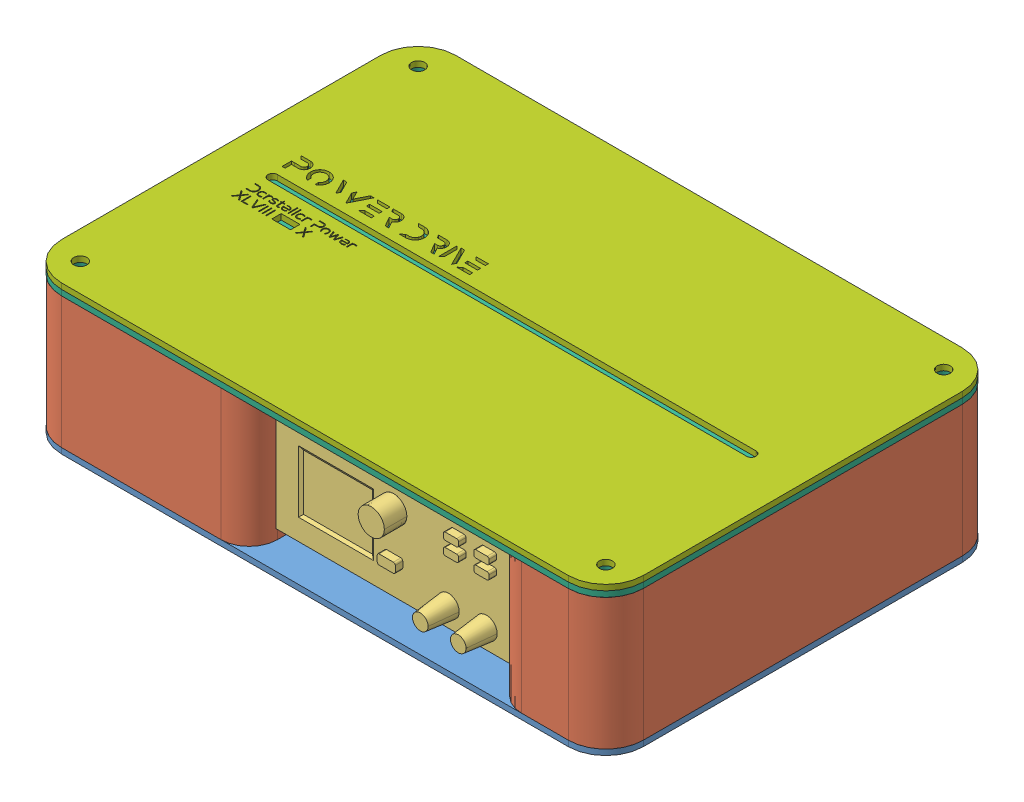
SolidWorks assembly model_1, configuration Default. Lengths in mm.
Overall size (310 79 212).
8 component instances, 8 part files, 19 mates.
Components (placement in the parent):
- bot_alu_3-1: bot_alu_3 [Default] at (129.9592 146.5535 227.5851) size (310 3 210)
- wall_1-1: wall_1 [Default] at (129.9592 149.5535 227.5851) size (310 70 210)
- XY6014.step-1: XY6014.step [Default] at (158.9592 184.0535 311.5851) x (0 0 1) z (-1 0 0) size (71 55.5 128.35)
- wall_2-1: wall_2 [Default] at (158.9592 149.5535 309.0851) size (150 69 20)
- 48v10a_template-1: 48v10a_template [Default] at (109.4592 154.5535 190.5851) size (214 49.5 114)
- top_mica_black-1: top_mica_black [Default] at (129.9592 219.5535 227.5851) size (310 3 210)
- top_alu_3-1: top_alu_3 [Default] at (129.9592 222.5535 227.5851) size (310 3 210)
- power_holder-1: power_holder [Default] at (129.9592 149.5535 190.0851) x (-1 0 0) z (0 0 -1) size (190 69 130)
Mates (geometry in assembly coordinates):
- Concentric1: concentric aligned: cylinder of bot_alu_3-1 through (-10.0408 149.5535 317.5851) axis (0 -1 0) radius 3.5; cylinder of wall_1-1 through (-10.0408 219.5535 317.5851) axis (0 -1 0) radius 2
- Concentric2: concentric aligned: cylinder of bot_alu_3-1 through (269.9592 149.5535 137.5851) axis (0 -1 0) radius 3.5; cylinder of wall_1-1 through (269.9592 219.5535 137.5851) axis (0 -1 0) radius 2
- Coincident1: coincident anti-aligned: plane of bot_alu_3-1 through (129.9592 149.5535 227.5851) normal (0 1 0); plane of wall_1-1 through (129.9592 149.5535 227.5851) normal (0 -1 0)
- Coincident2: coincident anti-aligned: plane of XY6014.step-1 through (158.9592 184.0535 311.5851) normal (0 0 -1); plane of wall_2-1 through (223.9592 218.5535 311.5851) normal (0 0 1)
- Coincident4: coincident anti-aligned: plane of XY6014.step-1 through (218.9592 159.0535 285.5851) normal (1 0 0); plane of wall_2-1 through (218.9592 209.0535 246.5851) normal (-1 0 0)
- Coincident5: coincident anti-aligned: plane of XY6014.step-1 through (218.9592 159.0535 285.5851) normal (0 -1 0); plane of wall_2-1 through (218.9592 159.0535 246.5851) normal (0 1 0)
- Coincident6: coincident anti-aligned: plane of bot_alu_3-1 through (129.9592 149.5535 227.5851) normal (0 1 0); plane of wall_2-1 through (158.9592 149.5535 309.0851) normal (0 -1 0)
- Concentric5: concentric aligned: cylinder of wall_1-1 through (-10.0408 219.5535 317.5851) axis (0 -1 0) radius 2; cylinder of top_mica_black-1 through (-10.0408 222.5535 317.5851) axis (0 -1 0) radius 3.5
- Concentric6: concentric aligned: cylinder of wall_1-1 through (-10.0408 219.5535 137.5851) axis (0 -1 0) radius 2; cylinder of top_mica_black-1 through (-10.0408 222.5535 137.5851) axis (0 -1 0) radius 3.5
- Coincident7: coincident anti-aligned: plane of wall_1-1 through (129.9592 219.5535 227.5851) normal (0 1 0); plane of top_mica_black-1 through (129.9592 219.5535 227.5851) normal (0 -1 0)
- Concentric7: concentric aligned: cylinder of top_mica_black-1 through (-10.0408 222.5535 137.5851) axis (0 -1 0) radius 3.5; cylinder of top_alu_3-1 through (-10.0408 225.5535 137.5851) axis (0 -1 0) radius 3.5
- Concentric8: concentric aligned: cylinder of top_mica_black-1 through (-10.0408 222.5535 317.5851) axis (0 -1 0) radius 3.5; cylinder of top_alu_3-1 through (-10.0408 225.5535 317.5851) axis (0 -1 0) radius 3.5
- Coincident8: coincident anti-aligned: plane of top_mica_black-1 through (129.9592 222.5535 227.5851) normal (0 1 0); plane of top_alu_3-1 through (129.9592 222.5535 227.5851) normal (0 -1 0)
- Coincident9: coincident anti-aligned: plane of bot_alu_3-1 through (129.9592 149.5535 227.5851) normal (0 1 0); plane of power_holder-1 through (129.9592 149.5535 190.0851) normal (0 -1 0)
- Coincident10: coincident anti-aligned: plane of wall_1-1 through (129.9592 219.5535 127.5851) normal (0 0 1); plane of power_holder-1 through (129.9592 218.5535 127.5851) normal (0 0 -1)
- Distance1: distance = 1 mm anti-aligned: plane of wall_1-1 through (54.9592 219.5535 227.5851) normal (1 0 0); plane of power_holder-1 through (55.9592 218.5535 190.0851) normal (-1 0 0)
- Concentric9: concentric aligned: cylinder of 48v10a_template-1 through (184.9592 192.5535 133.5851) axis (0 0 1) radius 2; cylinder of power_holder-1 through (184.9592 192.5535 192.5851) axis (0 0 1) radius 2.25
- Concentric10: concentric aligned: cylinder of 48v10a_template-1 through (34.9592 192.5535 133.5851) axis (0 0 1) radius 2; cylinder of power_holder-1 through (34.9592 192.5535 192.5851) axis (0 0 1) radius 2.25
- Coincident13: coincident anti-aligned: plane of 48v10a_template-1 through (216.4592 204.0535 247.5851) normal (0 0 1); plane of power_holder-1 through (129.9592 204.5535 247.5851) normal (0 0 -1)
